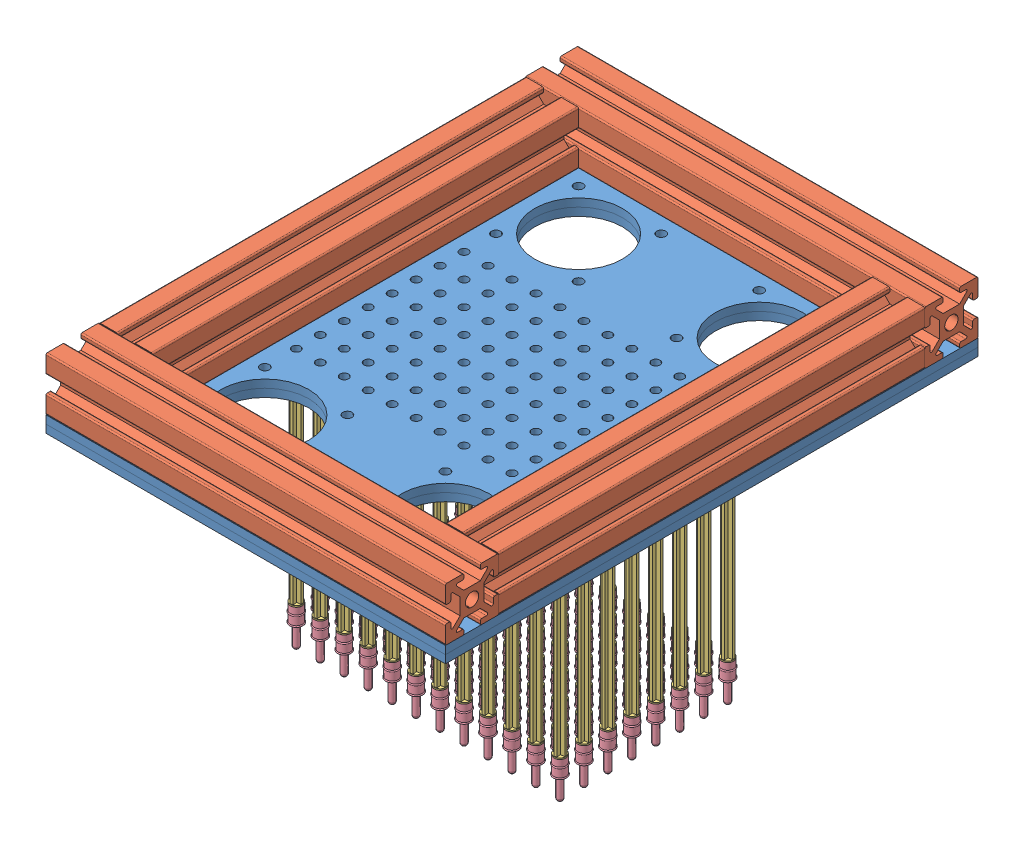
SolidWorks assembly plunger_plate_with_plungers, configuration Standard. Lengths in mm.
Overall size (150 117.5 200).
198 component instances, 4 part files, 20 mates.
Components (placement in the parent):
- plunger_plate-2: plunger_plate [Standard] at origin size (150 3 200)
- plunger_plate-4: plunger_plate [plunger_holder] at (0 -3 0) size (150 3 200)
- 20x20_extrude-1: 20x20_extrude [width4_smaller] at (-124.5 13 58.5) x (0 0 -1) z (1 0 0) size (20 20 150)
- 20x20_extrude-2: 20x20_extrude [width4_smaller] at (-124.5 13 -121.5) x (0 0 -1) z (1 0 0) size (20 20 150)
- 20x20_extrude-3: 20x20_extrude [width3] at (-114.5 13 -111.5) size (20 20 160)
- 20x20_extrude-4: 20x20_extrude [width3] at (15.5 13 -111.5) size (20 20 160)
- 1ml syringe piston-1: 1ml syringe piston [Standard] at (-99 -1 -63) x (-0.991081 0 0.133265) z (0 -1 0) size (8.5 8.5 83.75)
- plunger_tip-2: plunger_tip [Standard] at (-99 -94.5 -63) x (0.841515 0 -0.540233) z (0.540233 0 0.841515) size (5 15 5)
- plunger_tip-3: plunger_tip [Standard] at (-90 -94.5 -63) x (0.841515 0 -0.540233) z (0.540233 0 0.841515) size (5 15 5)
- plunger_tip-4: plunger_tip [Standard] at (-81 -94.5 -63) x (0.841515 0 -0.540233) z (0.540233 0 0.841515) size (5 15 5)
- plunger_tip-5: plunger_tip [Standard] at (-72 -94.5 -63) x (0.841515 0 -0.540233) z (0.540233 0 0.841515) size (5 15 5)
- plunger_tip-6: plunger_tip [Standard] at (-63 -94.5 -63) x (0.841515 0 -0.540233) z (0.540233 0 0.841515) size (5 15 5)
- plunger_tip-7: plunger_tip [Standard] at (-54 -94.5 -63) x (0.841515 0 -0.540233) z (0.540233 0 0.841515) size (5 15 5)
- plunger_tip-8: plunger_tip [Standard] at (-45 -94.5 -63) x (0.841515 0 -0.540233) z (0.540233 0 0.841515) size (5 15 5)
- plunger_tip-9: plunger_tip [Standard] at (-36 -94.5 -63) x (0.841515 0 -0.540233) z (0.540233 0 0.841515) size (5 15 5)
- plunger_tip-10: plunger_tip [Standard] at (-27 -94.5 -63) x (0.841515 0 -0.540233) z (0.540233 0 0.841515) size (5 15 5)
- plunger_tip-11: plunger_tip [Standard] at (-18 -94.5 -63) x (0.841515 0 -0.540233) z (0.540233 0 0.841515) size (5 15 5)
- plunger_tip-12: plunger_tip [Standard] at (-9 -94.5 -63) x (0.841515 0 -0.540233) z (0.540233 0 0.841515) size (5 15 5)
- plunger_tip-13: plunger_tip [Standard] at (0 -94.5 -63) x (0.841515 0 -0.540233) z (0.540233 0 0.841515) size (5 15 5)
- plunger_tip-14: plunger_tip [Standard] at (-99 -94.5 -54) x (0.841515 0 -0.540233) z (0.540233 0 0.841515) size (5 15 5)
- plunger_tip-15: plunger_tip [Standard] at (-90 -94.5 -54) x (0.841515 0 -0.540233) z (0.540233 0 0.841515) size (5 15 5)
- plunger_tip-16: plunger_tip [Standard] at (-81 -94.5 -54) x (0.841515 0 -0.540233) z (0.540233 0 0.841515) size (5 15 5)
- plunger_tip-17: plunger_tip [Standard] at (-72 -94.5 -54) x (0.841515 0 -0.540233) z (0.540233 0 0.841515) size (5 15 5)
- plunger_tip-18: plunger_tip [Standard] at (-63 -94.5 -54) x (0.841515 0 -0.540233) z (0.540233 0 0.841515) size (5 15 5)
- plunger_tip-19: plunger_tip [Standard] at (-54 -94.5 -54) x (0.841515 0 -0.540233) z (0.540233 0 0.841515) size (5 15 5)
- plunger_tip-20: plunger_tip [Standard] at (-45 -94.5 -54) x (0.841515 0 -0.540233) z (0.540233 0 0.841515) size (5 15 5)
- plunger_tip-21: plunger_tip [Standard] at (-36 -94.5 -54) x (0.841515 0 -0.540233) z (0.540233 0 0.841515) size (5 15 5)
- plunger_tip-22: plunger_tip [Standard] at (-27 -94.5 -54) x (0.841515 0 -0.540233) z (0.540233 0 0.841515) size (5 15 5)
- plunger_tip-23: plunger_tip [Standard] at (-18 -94.5 -54) x (0.841515 0 -0.540233) z (0.540233 0 0.841515) size (5 15 5)
- plunger_tip-24: plunger_tip [Standard] at (-9 -94.5 -54) x (0.841515 0 -0.540233) z (0.540233 0 0.841515) size (5 15 5)
- plunger_tip-25: plunger_tip [Standard] at (0 -94.5 -54) x (0.841515 0 -0.540233) z (0.540233 0 0.841515) size (5 15 5)
- plunger_tip-26: plunger_tip [Standard] at (-99 -94.5 -45) x (0.841515 0 -0.540233) z (0.540233 0 0.841515) size (5 15 5)
- plunger_tip-27: plunger_tip [Standard] at (-90 -94.5 -45) x (0.841515 0 -0.540233) z (0.540233 0 0.841515) size (5 15 5)
- plunger_tip-28: plunger_tip [Standard] at (-81 -94.5 -45) x (0.841515 0 -0.540233) z (0.540233 0 0.841515) size (5 15 5)
- plunger_tip-29: plunger_tip [Standard] at (-72 -94.5 -45) x (0.841515 0 -0.540233) z (0.540233 0 0.841515) size (5 15 5)
- plunger_tip-30: plunger_tip [Standard] at (-63 -94.5 -45) x (0.841515 0 -0.540233) z (0.540233 0 0.841515) size (5 15 5)
- plunger_tip-31: plunger_tip [Standard] at (-54 -94.5 -45) x (0.841515 0 -0.540233) z (0.540233 0 0.841515) size (5 15 5)
- plunger_tip-32: plunger_tip [Standard] at (-45 -94.5 -45) x (0.841515 0 -0.540233) z (0.540233 0 0.841515) size (5 15 5)
- plunger_tip-33: plunger_tip [Standard] at (-36 -94.5 -45) x (0.841515 0 -0.540233) z (0.540233 0 0.841515) size (5 15 5)
- plunger_tip-34: plunger_tip [Standard] at (-27 -94.5 -45) x (0.841515 0 -0.540233) z (0.540233 0 0.841515) size (5 15 5)
- plunger_tip-35: plunger_tip [Standard] at (-18 -94.5 -45) x (0.841515 0 -0.540233) z (0.540233 0 0.841515) size (5 15 5)
- plunger_tip-36: plunger_tip [Standard] at (-9 -94.5 -45) x (0.841515 0 -0.540233) z (0.540233 0 0.841515) size (5 15 5)
- plunger_tip-37: plunger_tip [Standard] at (0 -94.5 -45) x (0.841515 0 -0.540233) z (0.540233 0 0.841515) size (5 15 5)
- plunger_tip-38: plunger_tip [Standard] at (-99 -94.5 -36) x (0.841515 0 -0.540233) z (0.540233 0 0.841515) size (5 15 5)
- plunger_tip-39: plunger_tip [Standard] at (-90 -94.5 -36) x (0.841515 0 -0.540233) z (0.540233 0 0.841515) size (5 15 5)
- plunger_tip-40: plunger_tip [Standard] at (-81 -94.5 -36) x (0.841515 0 -0.540233) z (0.540233 0 0.841515) size (5 15 5)
- plunger_tip-41: plunger_tip [Standard] at (-72 -94.5 -36) x (0.841515 0 -0.540233) z (0.540233 0 0.841515) size (5 15 5)
- plunger_tip-42: plunger_tip [Standard] at (-63 -94.5 -36) x (0.841515 0 -0.540233) z (0.540233 0 0.841515) size (5 15 5)
- plunger_tip-43: plunger_tip [Standard] at (-54 -94.5 -36) x (0.841515 0 -0.540233) z (0.540233 0 0.841515) size (5 15 5)
- plunger_tip-44: plunger_tip [Standard] at (-45 -94.5 -36) x (0.841515 0 -0.540233) z (0.540233 0 0.841515) size (5 15 5)
- plunger_tip-45: plunger_tip [Standard] at (-36 -94.5 -36) x (0.841515 0 -0.540233) z (0.540233 0 0.841515) size (5 15 5)
- plunger_tip-46: plunger_tip [Standard] at (-27 -94.5 -36) x (0.841515 0 -0.540233) z (0.540233 0 0.841515) size (5 15 5)
- plunger_tip-47: plunger_tip [Standard] at (-18 -94.5 -36) x (0.841515 0 -0.540233) z (0.540233 0 0.841515) size (5 15 5)
- plunger_tip-48: plunger_tip [Standard] at (-9 -94.5 -36) x (0.841515 0 -0.540233) z (0.540233 0 0.841515) size (5 15 5)
- plunger_tip-49: plunger_tip [Standard] at (0 -94.5 -36) x (0.841515 0 -0.540233) z (0.540233 0 0.841515) size (5 15 5)
- plunger_tip-50: plunger_tip [Standard] at (-99 -94.5 -27) x (0.841515 0 -0.540233) z (0.540233 0 0.841515) size (5 15 5)
- plunger_tip-51: plunger_tip [Standard] at (-90 -94.5 -27) x (0.841515 0 -0.540233) z (0.540233 0 0.841515) size (5 15 5)
- plunger_tip-52: plunger_tip [Standard] at (-81 -94.5 -27) x (0.841515 0 -0.540233) z (0.540233 0 0.841515) size (5 15 5)
- plunger_tip-53: plunger_tip [Standard] at (-72 -94.5 -27) x (0.841515 0 -0.540233) z (0.540233 0 0.841515) size (5 15 5)
- plunger_tip-54: plunger_tip [Standard] at (-63 -94.5 -27) x (0.841515 0 -0.540233) z (0.540233 0 0.841515) size (5 15 5)
- plunger_tip-55: plunger_tip [Standard] at (-54 -94.5 -27) x (0.841515 0 -0.540233) z (0.540233 0 0.841515) size (5 15 5)
- plunger_tip-56: plunger_tip [Standard] at (-45 -94.5 -27) x (0.841515 0 -0.540233) z (0.540233 0 0.841515) size (5 15 5)
- plunger_tip-57: plunger_tip [Standard] at (-36 -94.5 -27) x (0.841515 0 -0.540233) z (0.540233 0 0.841515) size (5 15 5)
- plunger_tip-58: plunger_tip [Standard] at (-27 -94.5 -27) x (0.841515 0 -0.540233) z (0.540233 0 0.841515) size (5 15 5)
- plunger_tip-59: plunger_tip [Standard] at (-18 -94.5 -27) x (0.841515 0 -0.540233) z (0.540233 0 0.841515) size (5 15 5)
- plunger_tip-60: plunger_tip [Standard] at (-9 -94.5 -27) x (0.841515 0 -0.540233) z (0.540233 0 0.841515) size (5 15 5)
- plunger_tip-61: plunger_tip [Standard] at (0 -94.5 -27) x (0.841515 0 -0.540233) z (0.540233 0 0.841515) size (5 15 5)
- plunger_tip-62: plunger_tip [Standard] at (-99 -94.5 -18) x (0.841515 0 -0.540233) z (0.540233 0 0.841515) size (5 15 5)
- plunger_tip-63: plunger_tip [Standard] at (-90 -94.5 -18) x (0.841515 0 -0.540233) z (0.540233 0 0.841515) size (5 15 5)
- plunger_tip-64: plunger_tip [Standard] at (-81 -94.5 -18) x (0.841515 0 -0.540233) z (0.540233 0 0.841515) size (5 15 5)
- plunger_tip-65: plunger_tip [Standard] at (-72 -94.5 -18) x (0.841515 0 -0.540233) z (0.540233 0 0.841515) size (5 15 5)
- plunger_tip-66: plunger_tip [Standard] at (-63 -94.5 -18) x (0.841515 0 -0.540233) z (0.540233 0 0.841515) size (5 15 5)
- plunger_tip-67: plunger_tip [Standard] at (-54 -94.5 -18) x (0.841515 0 -0.540233) z (0.540233 0 0.841515) size (5 15 5)
- plunger_tip-68: plunger_tip [Standard] at (-45 -94.5 -18) x (0.841515 0 -0.540233) z (0.540233 0 0.841515) size (5 15 5)
- plunger_tip-69: plunger_tip [Standard] at (-36 -94.5 -18) x (0.841515 0 -0.540233) z (0.540233 0 0.841515) size (5 15 5)
- plunger_tip-70: plunger_tip [Standard] at (-27 -94.5 -18) x (0.841515 0 -0.540233) z (0.540233 0 0.841515) size (5 15 5)
- plunger_tip-71: plunger_tip [Standard] at (-18 -94.5 -18) x (0.841515 0 -0.540233) z (0.540233 0 0.841515) size (5 15 5)
- plunger_tip-72: plunger_tip [Standard] at (-9 -94.5 -18) x (0.841515 0 -0.540233) z (0.540233 0 0.841515) size (5 15 5)
- plunger_tip-73: plunger_tip [Standard] at (0 -94.5 -18) x (0.841515 0 -0.540233) z (0.540233 0 0.841515) size (5 15 5)
- plunger_tip-74: plunger_tip [Standard] at (-99 -94.5 -9) x (0.841515 0 -0.540233) z (0.540233 0 0.841515) size (5 15 5)
- plunger_tip-75: plunger_tip [Standard] at (-90 -94.5 -9) x (0.841515 0 -0.540233) z (0.540233 0 0.841515) size (5 15 5)
- plunger_tip-76: plunger_tip [Standard] at (-81 -94.5 -9) x (0.841515 0 -0.540233) z (0.540233 0 0.841515) size (5 15 5)
- plunger_tip-77: plunger_tip [Standard] at (-72 -94.5 -9) x (0.841515 0 -0.540233) z (0.540233 0 0.841515) size (5 15 5)
- plunger_tip-78: plunger_tip [Standard] at (-63 -94.5 -9) x (0.841515 0 -0.540233) z (0.540233 0 0.841515) size (5 15 5)
- plunger_tip-79: plunger_tip [Standard] at (-54 -94.5 -9) x (0.841515 0 -0.540233) z (0.540233 0 0.841515) size (5 15 5)
- plunger_tip-80: plunger_tip [Standard] at (-45 -94.5 -9) x (0.841515 0 -0.540233) z (0.540233 0 0.841515) size (5 15 5)
- plunger_tip-81: plunger_tip [Standard] at (-36 -94.5 -9) x (0.841515 0 -0.540233) z (0.540233 0 0.841515) size (5 15 5)
- plunger_tip-82: plunger_tip [Standard] at (-27 -94.5 -9) x (0.841515 0 -0.540233) z (0.540233 0 0.841515) size (5 15 5)
- plunger_tip-83: plunger_tip [Standard] at (-18 -94.5 -9) x (0.841515 0 -0.540233) z (0.540233 0 0.841515) size (5 15 5)
- plunger_tip-84: plunger_tip [Standard] at (-9 -94.5 -9) x (0.841515 0 -0.540233) z (0.540233 0 0.841515) size (5 15 5)
- plunger_tip-85: plunger_tip [Standard] at (0 -94.5 -9) x (0.841515 0 -0.540233) z (0.540233 0 0.841515) size (5 15 5)
- plunger_tip-86: plunger_tip [Standard] at (-99 -94.5 0) x (0.841515 0 -0.540233) z (0.540233 0 0.841515) size (5 15 5)
- plunger_tip-87: plunger_tip [Standard] at (-90 -94.5 0) x (0.841515 0 -0.540233) z (0.540233 0 0.841515) size (5 15 5)
- plunger_tip-88: plunger_tip [Standard] at (-81 -94.5 0) x (0.841515 0 -0.540233) z (0.540233 0 0.841515) size (5 15 5)
- plunger_tip-89: plunger_tip [Standard] at (-72 -94.5 0) x (0.841515 0 -0.540233) z (0.540233 0 0.841515) size (5 15 5)
- plunger_tip-90: plunger_tip [Standard] at (-63 -94.5 0) x (0.841515 0 -0.540233) z (0.540233 0 0.841515) size (5 15 5)
- plunger_tip-91: plunger_tip [Standard] at (-54 -94.5 0) x (0.841515 0 -0.540233) z (0.540233 0 0.841515) size (5 15 5)
- plunger_tip-92: plunger_tip [Standard] at (-45 -94.5 0) x (0.841515 0 -0.540233) z (0.540233 0 0.841515) size (5 15 5)
- plunger_tip-93: plunger_tip [Standard] at (-36 -94.5 0) x (0.841515 0 -0.540233) z (0.540233 0 0.841515) size (5 15 5)
- plunger_tip-94: plunger_tip [Standard] at (-27 -94.5 0) x (0.841515 0 -0.540233) z (0.540233 0 0.841515) size (5 15 5)
- plunger_tip-95: plunger_tip [Standard] at (-18 -94.5 0) x (0.841515 0 -0.540233) z (0.540233 0 0.841515) size (5 15 5)
- plunger_tip-96: plunger_tip [Standard] at (-9 -94.5 0) x (0.841515 0 -0.540233) z (0.540233 0 0.841515) size (5 15 5)
- plunger_tip-97: plunger_tip [Standard] at (0 -94.5 0) x (0.841515 0 -0.540233) z (0.540233 0 0.841515) size (5 15 5)
- 1ml syringe piston-2: 1ml syringe piston [Standard] at (-90 -1 -63) x (-0.991081 0 0.133265) z (0 -1 0) size (8.5 8.5 83.75)
- 1ml syringe piston-3: 1ml syringe piston [Standard] at (-81 -1 -63) x (-0.991081 0 0.133265) z (0 -1 0) size (8.5 8.5 83.75)
- 1ml syringe piston-4: 1ml syringe piston [Standard] at (-72 -1 -63) x (-0.991081 0 0.133265) z (0 -1 0) size (8.5 8.5 83.75)
- 1ml syringe piston-5: 1ml syringe piston [Standard] at (-63 -1 -63) x (-0.991081 0 0.133265) z (0 -1 0) size (8.5 8.5 83.75)
- 1ml syringe piston-6: 1ml syringe piston [Standard] at (-54 -1 -63) x (-0.991081 0 0.133265) z (0 -1 0) size (8.5 8.5 83.75)
- 1ml syringe piston-7: 1ml syringe piston [Standard] at (-45 -1 -63) x (-0.991081 0 0.133265) z (0 -1 0) size (8.5 8.5 83.75)
- 1ml syringe piston-8: 1ml syringe piston [Standard] at (-36 -1 -63) x (-0.991081 0 0.133265) z (0 -1 0) size (8.5 8.5 83.75)
- 1ml syringe piston-9: 1ml syringe piston [Standard] at (-27 -1 -63) x (-0.991081 0 0.133265) z (0 -1 0) size (8.5 8.5 83.75)
- 1ml syringe piston-10: 1ml syringe piston [Standard] at (-18 -1 -63) x (-0.991081 0 0.133265) z (0 -1 0) size (8.5 8.5 83.75)
- 1ml syringe piston-11: 1ml syringe piston [Standard] at (-9 -1 -63) x (-0.991081 0 0.133265) z (0 -1 0) size (8.5 8.5 83.75)
- 1ml syringe piston-12: 1ml syringe piston [Standard] at (0 -1 -63) x (-0.991081 0 0.133265) z (0 -1 0) size (8.5 8.5 83.75)
- 1ml syringe piston-13: 1ml syringe piston [Standard] at (-99 -1 -54) x (-0.991081 0 0.133265) z (0 -1 0) size (8.5 8.5 83.75)
- 1ml syringe piston-14: 1ml syringe piston [Standard] at (-90 -1 -54) x (-0.991081 0 0.133265) z (0 -1 0) size (8.5 8.5 83.75)
- 1ml syringe piston-15: 1ml syringe piston [Standard] at (-81 -1 -54) x (-0.991081 0 0.133265) z (0 -1 0) size (8.5 8.5 83.75)
- 1ml syringe piston-16: 1ml syringe piston [Standard] at (-72 -1 -54) x (-0.991081 0 0.133265) z (0 -1 0) size (8.5 8.5 83.75)
- 1ml syringe piston-17: 1ml syringe piston [Standard] at (-63 -1 -54) x (-0.991081 0 0.133265) z (0 -1 0) size (8.5 8.5 83.75)
- 1ml syringe piston-18: 1ml syringe piston [Standard] at (-54 -1 -54) x (-0.991081 0 0.133265) z (0 -1 0) size (8.5 8.5 83.75)
- 1ml syringe piston-19: 1ml syringe piston [Standard] at (-45 -1 -54) x (-0.991081 0 0.133265) z (0 -1 0) size (8.5 8.5 83.75)
- 1ml syringe piston-20: 1ml syringe piston [Standard] at (-36 -1 -54) x (-0.991081 0 0.133265) z (0 -1 0) size (8.5 8.5 83.75)
- 1ml syringe piston-21: 1ml syringe piston [Standard] at (-27 -1 -54) x (-0.991081 0 0.133265) z (0 -1 0) size (8.5 8.5 83.75)
- 1ml syringe piston-22: 1ml syringe piston [Standard] at (-18 -1 -54) x (-0.991081 0 0.133265) z (0 -1 0) size (8.5 8.5 83.75)
- 1ml syringe piston-23: 1ml syringe piston [Standard] at (-9 -1 -54) x (-0.991081 0 0.133265) z (0 -1 0) size (8.5 8.5 83.75)
- 1ml syringe piston-24: 1ml syringe piston [Standard] at (0 -1 -54) x (-0.991081 0 0.133265) z (0 -1 0) size (8.5 8.5 83.75)
- 1ml syringe piston-25: 1ml syringe piston [Standard] at (-99 -1 -45) x (-0.991081 0 0.133265) z (0 -1 0) size (8.5 8.5 83.75)
- 1ml syringe piston-26: 1ml syringe piston [Standard] at (-90 -1 -45) x (-0.991081 0 0.133265) z (0 -1 0) size (8.5 8.5 83.75)
- 1ml syringe piston-27: 1ml syringe piston [Standard] at (-81 -1 -45) x (-0.991081 0 0.133265) z (0 -1 0) size (8.5 8.5 83.75)
- 1ml syringe piston-28: 1ml syringe piston [Standard] at (-72 -1 -45) x (-0.991081 0 0.133265) z (0 -1 0) size (8.5 8.5 83.75)
- 1ml syringe piston-29: 1ml syringe piston [Standard] at (-63 -1 -45) x (-0.991081 0 0.133265) z (0 -1 0) size (8.5 8.5 83.75)
- 1ml syringe piston-30: 1ml syringe piston [Standard] at (-54 -1 -45) x (-0.991081 0 0.133265) z (0 -1 0) size (8.5 8.5 83.75)
- 1ml syringe piston-31: 1ml syringe piston [Standard] at (-45 -1 -45) x (-0.991081 0 0.133265) z (0 -1 0) size (8.5 8.5 83.75)
- 1ml syringe piston-32: 1ml syringe piston [Standard] at (-36 -1 -45) x (-0.991081 0 0.133265) z (0 -1 0) size (8.5 8.5 83.75)
- 1ml syringe piston-33: 1ml syringe piston [Standard] at (-27 -1 -45) x (-0.991081 0 0.133265) z (0 -1 0) size (8.5 8.5 83.75)
- 1ml syringe piston-34: 1ml syringe piston [Standard] at (-18 -1 -45) x (-0.991081 0 0.133265) z (0 -1 0) size (8.5 8.5 83.75)
- 1ml syringe piston-35: 1ml syringe piston [Standard] at (-9 -1 -45) x (-0.991081 0 0.133265) z (0 -1 0) size (8.5 8.5 83.75)
- 1ml syringe piston-36: 1ml syringe piston [Standard] at (0 -1 -45) x (-0.991081 0 0.133265) z (0 -1 0) size (8.5 8.5 83.75)
- 1ml syringe piston-37: 1ml syringe piston [Standard] at (-99 -1 -36) x (-0.991081 0 0.133265) z (0 -1 0) size (8.5 8.5 83.75)
- 1ml syringe piston-38: 1ml syringe piston [Standard] at (-90 -1 -36) x (-0.991081 0 0.133265) z (0 -1 0) size (8.5 8.5 83.75)
- 1ml syringe piston-39: 1ml syringe piston [Standard] at (-81 -1 -36) x (-0.991081 0 0.133265) z (0 -1 0) size (8.5 8.5 83.75)
- 1ml syringe piston-40: 1ml syringe piston [Standard] at (-72 -1 -36) x (-0.991081 0 0.133265) z (0 -1 0) size (8.5 8.5 83.75)
- 1ml syringe piston-41: 1ml syringe piston [Standard] at (-63 -1 -36) x (-0.991081 0 0.133265) z (0 -1 0) size (8.5 8.5 83.75)
- 1ml syringe piston-42: 1ml syringe piston [Standard] at (-54 -1 -36) x (-0.991081 0 0.133265) z (0 -1 0) size (8.5 8.5 83.75)
- 1ml syringe piston-43: 1ml syringe piston [Standard] at (-45 -1 -36) x (-0.991081 0 0.133265) z (0 -1 0) size (8.5 8.5 83.75)
- 1ml syringe piston-44: 1ml syringe piston [Standard] at (-36 -1 -36) x (-0.991081 0 0.133265) z (0 -1 0) size (8.5 8.5 83.75)
- 1ml syringe piston-45: 1ml syringe piston [Standard] at (-27 -1 -36) x (-0.991081 0 0.133265) z (0 -1 0) size (8.5 8.5 83.75)
- 1ml syringe piston-46: 1ml syringe piston [Standard] at (-18 -1 -36) x (-0.991081 0 0.133265) z (0 -1 0) size (8.5 8.5 83.75)
- 1ml syringe piston-47: 1ml syringe piston [Standard] at (-9 -1 -36) x (-0.991081 0 0.133265) z (0 -1 0) size (8.5 8.5 83.75)
- 1ml syringe piston-48: 1ml syringe piston [Standard] at (0 -1 -36) x (-0.991081 0 0.133265) z (0 -1 0) size (8.5 8.5 83.75)
- 1ml syringe piston-49: 1ml syringe piston [Standard] at (-99 -1 -27) x (-0.991081 0 0.133265) z (0 -1 0) size (8.5 8.5 83.75)
- 1ml syringe piston-50: 1ml syringe piston [Standard] at (-90 -1 -27) x (-0.991081 0 0.133265) z (0 -1 0) size (8.5 8.5 83.75)
- 1ml syringe piston-51: 1ml syringe piston [Standard] at (-81 -1 -27) x (-0.991081 0 0.133265) z (0 -1 0) size (8.5 8.5 83.75)
- 1ml syringe piston-52: 1ml syringe piston [Standard] at (-72 -1 -27) x (-0.991081 0 0.133265) z (0 -1 0) size (8.5 8.5 83.75)
- 1ml syringe piston-53: 1ml syringe piston [Standard] at (-63 -1 -27) x (-0.991081 0 0.133265) z (0 -1 0) size (8.5 8.5 83.75)
- 1ml syringe piston-54: 1ml syringe piston [Standard] at (-54 -1 -27) x (-0.991081 0 0.133265) z (0 -1 0) size (8.5 8.5 83.75)
- 1ml syringe piston-55: 1ml syringe piston [Standard] at (-45 -1 -27) x (-0.991081 0 0.133265) z (0 -1 0) size (8.5 8.5 83.75)
- 1ml syringe piston-56: 1ml syringe piston [Standard] at (-36 -1 -27) x (-0.991081 0 0.133265) z (0 -1 0) size (8.5 8.5 83.75)
- 1ml syringe piston-57: 1ml syringe piston [Standard] at (-27 -1 -27) x (-0.991081 0 0.133265) z (0 -1 0) size (8.5 8.5 83.75)
- 1ml syringe piston-58: 1ml syringe piston [Standard] at (-18 -1 -27) x (-0.991081 0 0.133265) z (0 -1 0) size (8.5 8.5 83.75)
- 1ml syringe piston-59: 1ml syringe piston [Standard] at (-9 -1 -27) x (-0.991081 0 0.133265) z (0 -1 0) size (8.5 8.5 83.75)
- 1ml syringe piston-60: 1ml syringe piston [Standard] at (0 -1 -27) x (-0.991081 0 0.133265) z (0 -1 0) size (8.5 8.5 83.75)
- 1ml syringe piston-61: 1ml syringe piston [Standard] at (-99 -1 -18) x (-0.991081 0 0.133265) z (0 -1 0) size (8.5 8.5 83.75)
- 1ml syringe piston-62: 1ml syringe piston [Standard] at (-90 -1 -18) x (-0.991081 0 0.133265) z (0 -1 0) size (8.5 8.5 83.75)
- 1ml syringe piston-63: 1ml syringe piston [Standard] at (-81 -1 -18) x (-0.991081 0 0.133265) z (0 -1 0) size (8.5 8.5 83.75)
- 1ml syringe piston-64: 1ml syringe piston [Standard] at (-72 -1 -18) x (-0.991081 0 0.133265) z (0 -1 0) size (8.5 8.5 83.75)
- 1ml syringe piston-65: 1ml syringe piston [Standard] at (-63 -1 -18) x (-0.991081 0 0.133265) z (0 -1 0) size (8.5 8.5 83.75)
- 1ml syringe piston-66: 1ml syringe piston [Standard] at (-54 -1 -18) x (-0.991081 0 0.133265) z (0 -1 0) size (8.5 8.5 83.75)
- 1ml syringe piston-67: 1ml syringe piston [Standard] at (-45 -1 -18) x (-0.991081 0 0.133265) z (0 -1 0) size (8.5 8.5 83.75)
- 1ml syringe piston-68: 1ml syringe piston [Standard] at (-36 -1 -18) x (-0.991081 0 0.133265) z (0 -1 0) size (8.5 8.5 83.75)
- 1ml syringe piston-69: 1ml syringe piston [Standard] at (-27 -1 -18) x (-0.991081 0 0.133265) z (0 -1 0) size (8.5 8.5 83.75)
- 1ml syringe piston-70: 1ml syringe piston [Standard] at (-18 -1 -18) x (-0.991081 0 0.133265) z (0 -1 0) size (8.5 8.5 83.75)
- 1ml syringe piston-71: 1ml syringe piston [Standard] at (-9 -1 -18) x (-0.991081 0 0.133265) z (0 -1 0) size (8.5 8.5 83.75)
- 1ml syringe piston-72: 1ml syringe piston [Standard] at (0 -1 -18) x (-0.991081 0 0.133265) z (0 -1 0) size (8.5 8.5 83.75)
- 1ml syringe piston-73: 1ml syringe piston [Standard] at (-99 -1 -9) x (-0.991081 0 0.133265) z (0 -1 0) size (8.5 8.5 83.75)
- 1ml syringe piston-74: 1ml syringe piston [Standard] at (-90 -1 -9) x (-0.991081 0 0.133265) z (0 -1 0) size (8.5 8.5 83.75)
- 1ml syringe piston-75: 1ml syringe piston [Standard] at (-81 -1 -9) x (-0.991081 0 0.133265) z (0 -1 0) size (8.5 8.5 83.75)
- 1ml syringe piston-76: 1ml syringe piston [Standard] at (-72 -1 -9) x (-0.991081 0 0.133265) z (0 -1 0) size (8.5 8.5 83.75)
- 1ml syringe piston-77: 1ml syringe piston [Standard] at (-63 -1 -9) x (-0.991081 0 0.133265) z (0 -1 0) size (8.5 8.5 83.75)
- 1ml syringe piston-78: 1ml syringe piston [Standard] at (-54 -1 -9) x (-0.991081 0 0.133265) z (0 -1 0) size (8.5 8.5 83.75)
- 1ml syringe piston-79: 1ml syringe piston [Standard] at (-45 -1 -9) x (-0.991081 0 0.133265) z (0 -1 0) size (8.5 8.5 83.75)
- 1ml syringe piston-80: 1ml syringe piston [Standard] at (-36 -1 -9) x (-0.991081 0 0.133265) z (0 -1 0) size (8.5 8.5 83.75)
- 1ml syringe piston-81: 1ml syringe piston [Standard] at (-27 -1 -9) x (-0.991081 0 0.133265) z (0 -1 0) size (8.5 8.5 83.75)
- 1ml syringe piston-82: 1ml syringe piston [Standard] at (-18 -1 -9) x (-0.991081 0 0.133265) z (0 -1 0) size (8.5 8.5 83.75)
- 1ml syringe piston-83: 1ml syringe piston [Standard] at (-9 -1 -9) x (-0.991081 0 0.133265) z (0 -1 0) size (8.5 8.5 83.75)
- 1ml syringe piston-84: 1ml syringe piston [Standard] at (0 -1 -9) x (-0.991081 0 0.133265) z (0 -1 0) size (8.5 8.5 83.75)
- 1ml syringe piston-85: 1ml syringe piston [Standard] at (-99 -1 0) x (-0.991081 0 0.133265) z (0 -1 0) size (8.5 8.5 83.75)
- 1ml syringe piston-86: 1ml syringe piston [Standard] at (-90 -1 0) x (-0.991081 0 0.133265) z (0 -1 0) size (8.5 8.5 83.75)
- 1ml syringe piston-87: 1ml syringe piston [Standard] at (-81 -1 0) x (-0.991081 0 0.133265) z (0 -1 0) size (8.5 8.5 83.75)
- 1ml syringe piston-88: 1ml syringe piston [Standard] at (-72 -1 0) x (-0.991081 0 0.133265) z (0 -1 0) size (8.5 8.5 83.75)
- 1ml syringe piston-89: 1ml syringe piston [Standard] at (-63 -1 0) x (-0.991081 0 0.133265) z (0 -1 0) size (8.5 8.5 83.75)
- 1ml syringe piston-90: 1ml syringe piston [Standard] at (-54 -1 0) x (-0.991081 0 0.133265) z (0 -1 0) size (8.5 8.5 83.75)
- 1ml syringe piston-91: 1ml syringe piston [Standard] at (-45 -1 0) x (-0.991081 0 0.133265) z (0 -1 0) size (8.5 8.5 83.75)
- 1ml syringe piston-92: 1ml syringe piston [Standard] at (-36 -1 0) x (-0.991081 0 0.133265) z (0 -1 0) size (8.5 8.5 83.75)
- 1ml syringe piston-93: 1ml syringe piston [Standard] at (-27 -1 0) x (-0.991081 0 0.133265) z (0 -1 0) size (8.5 8.5 83.75)
- 1ml syringe piston-94: 1ml syringe piston [Standard] at (-18 -1 0) x (-0.991081 0 0.133265) z (0 -1 0) size (8.5 8.5 83.75)
- 1ml syringe piston-95: 1ml syringe piston [Standard] at (-9 -1 0) x (-0.991081 0 0.133265) z (0 -1 0) size (8.5 8.5 83.75)
- 1ml syringe piston-96: 1ml syringe piston [Standard] at (0 -1 0) x (-0.991081 0 0.133265) z (0 -1 0) size (8.5 8.5 83.75)
Mates (geometry in assembly coordinates):
- Deckungsgleich4: coordinate: point of plunger_plate-2
- Deckungsgleich9: coincident aligned: plane of 20x20_extrude-1 through (25.5 23 55.4) normal (0 1 0); plane of 20x20_extrude-2 through (25.5 23 -124.6) normal (0 1 0)
- Deckungsgleich14: coincident aligned: plane of 20x20_extrude-1 through (25.5 23 55.4) normal (0 1 0); plane of 20x20_extrude-3 through (-124.5 23 48.5) normal (0 1 0)
- Deckungsgleich15: coincident aligned: plane of 20x20_extrude-1 through (25.5 23 55.4) normal (0 1 0); plane of 20x20_extrude-4 through (5.5 23 48.5) normal (0 1 0)
- Deckungsgleich20: coincident aligned: plane of plunger_plate-2 through (-103.5 -125.5388 -131.5) normal (0 0 -1); plane of 20x20_extrude-2 through (25.5 9.9 -131.5) normal (0 0 -1)
- Deckungsgleich21: coincident aligned: plane of plunger_plate-2 through (25.5 -201.0995 68.5) normal (1 0 0); plane of 20x20_extrude-4 through (25.5 9.9 48.5) normal (1 0 0)
- Deckungsgleich22: coincident anti-aligned: plane of plunger_plate-2 through (-46 3 -54) normal (0 1 0); plane of 20x20_extrude-4 through (25.5 3 48.5) normal (0 -1 0)
- Deckungsgleich23: coincident anti-aligned: plane of 20x20_extrude-1 through (25.5 23 48.5) normal (0 0 -1); plane of 20x20_extrude-4 through (15.5 13 48.5) normal (0 0 1)
- Deckungsgleich24: coincident aligned: plane of 20x20_extrude-1 through (25.5 13 58.5) normal (1 0 0); plane of 20x20_extrude-4 through (25.5 23 48.5) normal (1 0 0)
- Deckungsgleich25: coincident aligned: plane of plunger_plate-2 through (-103.5 -125.5388 68.5) normal (0 0 1); plane of 20x20_extrude-1 through (25.5 16.1 68.5) normal (0 0 1)
- Deckungsgleich26: coincident aligned: plane of 20x20_extrude-2 through (25.5 13 -121.5) normal (1 0 0); plane of 20x20_extrude-4 through (25.5 23 48.5) normal (1 0 0)
- Deckungsgleich27: coincident anti-aligned: plane of 20x20_extrude-1 through (25.5 9.9 48.5) normal (0 0 -1); plane of 20x20_extrude-3 through (-114.5 13 48.5) normal (0 0 1)
- Deckungsgleich28: coincident aligned: plane of 20x20_extrude-1 through (-124.5 13 58.5) normal (-1 0 0); plane of 20x20_extrude-3 through (-124.5 3 48.5) normal (-1 0 0)
- Deckungsgleich41: coincident aligned: plane of plunger_plate-2 through (-103.5 -125.5388 -131.5) normal (0 0 -1); plane of plunger_plate-4 through (-103.5 -128.5388 -131.5) normal (0 0 -1)
- Deckungsgleich42: coincident aligned: plane of plunger_plate-2 through (-124.5 -201.0995 -131.5) normal (-1 0 0); plane of plunger_plate-4 through (-124.5 -204.0995 -131.5) normal (-1 0 0)
- Deckungsgleich43: coincident anti-aligned: plane of plunger_plate-2 through (-46 0 -54) normal (0 -1 0); plane of plunger_plate-4 through (-46 0 -54) normal (0 1 0)
- Deckungsgleich44: coincident anti-aligned: plane of plunger_plate-2 through (-46 0 -54) normal (0 -1 0); plane of 1ml syringe piston-1 through (-99 0 -63) normal (0 1 0)
- Konzentrisch7: concentric aligned: circle of 1ml syringe piston-1; circle of plunger_tip-2
- Deckungsgleich46: coincident anti-aligned: plane of 1ml syringe piston-1 through (-99.2998 -79.5 -65.2299) normal (0 -1 0); plane of plunger_tip-2 through (-99 -79.5 -63) normal (0 1 0)
- Konzentrisch8: concentric anti-aligned: circle of plunger_plate-4; circle of 1ml syringe piston-1
